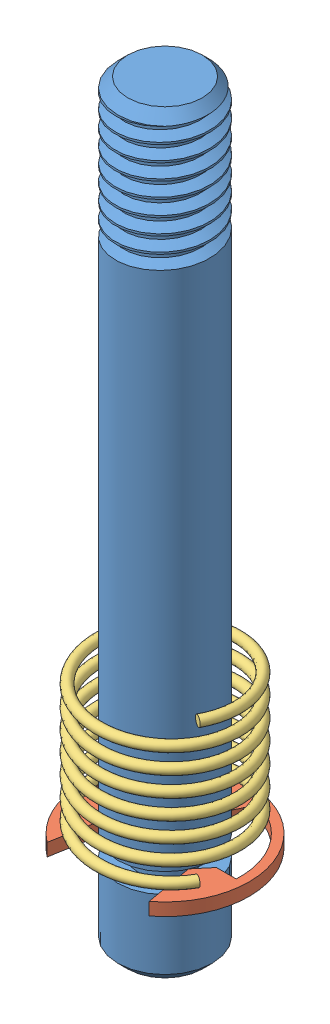
SolidWorks assembly Lock Pin Assembly, configuration Default. Lengths in mm.
Overall size (10.66 38.1 10.66).
3 component instances, 3 part files, 7 mates.
Components (placement in the parent):
- Lock Pin-1: Lock Pin [Default] at (19.6783 8.9879 50.5331) size (4.8 38.1 4.76)
- E-Ring-1: E-Ring [Default] at (19.6783 13.3479 50.5331) size (8.5 0.64 7.63)
- Spring-1: Spring [Default] at (19.6783 14.2379 50.5331) x (-0.902988 0 -0.429666) z (0 1 0) size (8 8 7.5)
Mates (geometry in assembly coordinates):
- Concentric1: concentric: cylinder of Lock Pin-1 through (19.6783 8.9879 50.5331) axis (0 -1 0) radius 1.3813; cylinder of E-Ring-1 through (19.6783 13.9879 50.5331) axis (0 -1 0) radius 1.8
- Coincident1: coincident: plane of Lock Pin-1 through (18.297 13.9879 50.5331) normal (0 -1 0); plane of E-Ring-1 through (19.6783 13.9879 50.5331) normal (0 1 0)
- Concentric2: concentric: cylinder of Lock Pin-1 through (19.6783 72.4879 50.5331) axis (0 -1 0) radius 3; cylinder of ? through (19.6783 25.9879 50.5331) axis (0 -1 0) radius 3.1
- Coincident2: coincident: plane of E-Ring-1 through (19.6783 24.9879 50.5331) normal (0 1 0); plane of ? through (19.6783 24.9879 50.5331) normal (0 -1 0)
- Concentric3: concentric: cylinder of Lock Pin-1 through (19.6783 72.4879 50.5331) axis (0 -1 0) radius 3; cylinder of ? through (19.6783 37.0663 50.5331) axis (0 -1 0) radius 3.1
- Concentric5: concentric: cylinder of Lock Pin-1 through (19.6783 47.0879 50.5331) axis (0 -1 0) radius 2.3813; circle of Spring-1
- Tangent5: tangent: plane of E-Ring-1 through (19.6783 13.9879 50.5331) normal (0 1 0); circle of Spring-1
